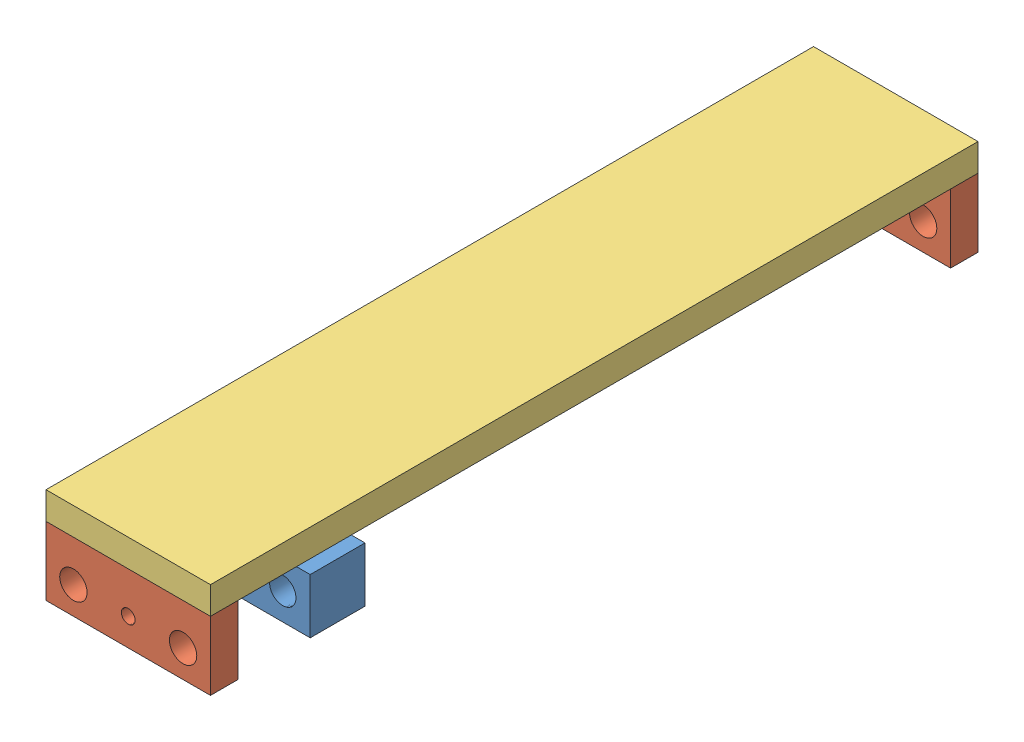
SolidWorks assembly linear_axis, configuration Default. Lengths in mm.
Overall size (76.2 44.45 355.6).
4 component instances, 3 part files, 10 mates.
Components (placement in the parent):
- Linear Slide^linear_axis-1: Linear Slide^linear_axis [Default] at (38.1 -19.05 -71.6017) x (-1 0 0) z (0 0 1) size (76.2 25.4 25.4) (virtual)
- End block^linear_axis-1: End block^linear_axis [Default] at (38.1 -19.05 -12.7) x (-1 0 0) z (0 0 1) size (76.2 38.1 12.7) (virtual)
- End block^linear_axis-2: End block^linear_axis [Default] at (38.1 -19.05 -355.6) x (-1 0 0) z (0 0 1) size (76.2 38.1 12.7) (virtual)
- Part1^linear_axis-1: Part1^linear_axis [Default] x (1 0 0) z (0 1 0) size (76.2 355.6 12.7) (virtual)
Mates (geometry in assembly coordinates):
- Concentric1: concentric aligned: circle of Linear Slide^linear_axis-1; circle of End block^linear_axis-1
- Concentric2: concentric aligned: circle of Linear Slide^linear_axis-1; circle of End block^linear_axis-2
- Parallel5: parallel aligned: plane of Linear Slide^linear_axis-1 through (76.2 -31.75 -46.2017) normal (0 -1 0); plane of End block^linear_axis-1 through (38.1 -31.75 0) normal (0 -1 0)
- Coincident7: coincident aligned: plane of Linear Slide^linear_axis-1 through (76.2 -31.75 -46.2017) normal (0 -1 0); plane of End block^linear_axis-2 through (38.1 -31.75 -342.9) normal (0 -1 0)
- InPlace1: in place: plane of Part1^linear_axis-1 through (0 0 0) normal (0 1 0); moOrthogonalPlaneRef_w of Part1^linear_axis-1 through (0 0 0) normal (0 0 -1); line of Part1^linear_axis-1 through (55 -55 0) axis (0 0 1); unknown of Part1^linear_axis-1
- Coincident8: coincident aligned: plane of Part1^linear_axis-1; plane of assembly
- Coincident9: coincident aligned: plane of Part1^linear_axis-1 through (0 0 0) normal (0 0 -1); moOrthogonalPlaneRef_w of assembly
- Coincident10: coincident anti-aligned: plane of Part1^linear_axis-1; moOrthogonalPlaneRef_w of assembly
- Coincident11: coincident aligned: circle of End block^linear_axis-1; circle of Part1^linear_axis-1
- Coincident12: coincident anti-aligned: circle of End block^linear_axis-2; circle of Part1^linear_axis-1
